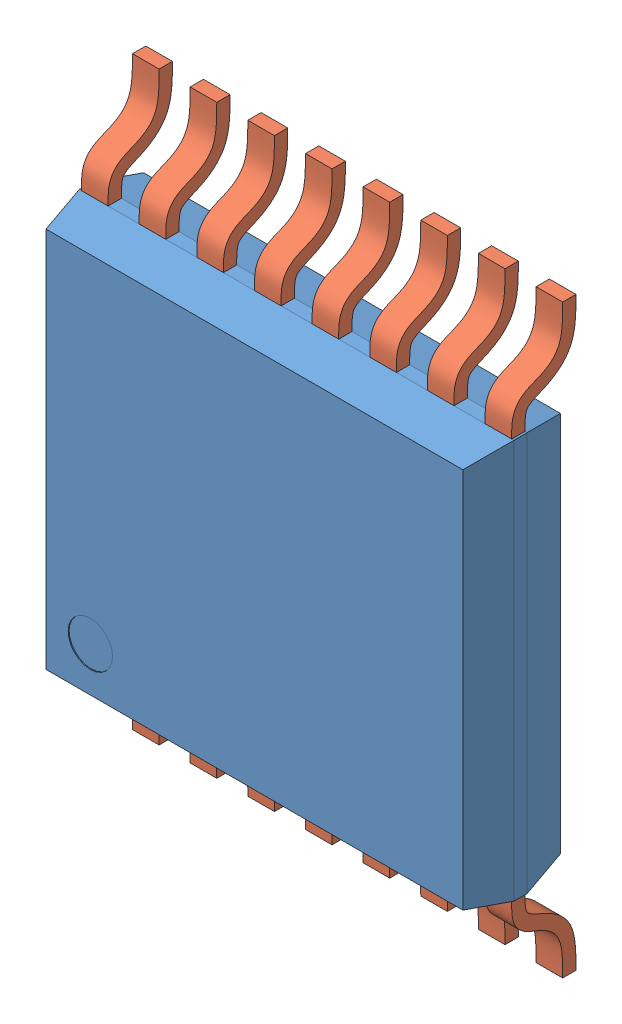
SolidWorks assembly Assem4, configuration Default. Lengths in mm.
Overall size (4.9 6.6 1.2).
17 component instances, 2 part files, 7 mates.
Components (placement in the parent):
- Body-1: Body [Default] at (0 0 0.65) size (4.9 4.5 1.1)
- Pin-1: Pin [Default] at (-2.275 -3.3 0.075) x (0 1 0) z (0 0 -1) size (1.05 0.3 0.73)
- Pin-2: Pin [Default] at (-1.625 -3.3 0.075) x (0 1 0) z (0 0 -1) size (1.05 0.3 0.73)
- Pin-3: Pin [Default] at (-0.975 -3.3 0.075) x (0 1 0) z (0 0 -1) size (1.05 0.3 0.73)
- Pin-4: Pin [Default] at (-0.325 -3.3 0.075) x (0 1 0) z (0 0 -1) size (1.05 0.3 0.73)
- Pin-5: Pin [Default] at (0.325 -3.3 0.075) x (0 1 0) z (0 0 -1) size (1.05 0.3 0.73)
- Pin-6: Pin [Default] at (0.975 -3.3 0.075) x (0 1 0) z (0 0 -1) size (1.05 0.3 0.73)
- Pin-7: Pin [Default] at (1.625 -3.3 0.075) x (0 1 0) z (0 0 -1) size (1.05 0.3 0.73)
- Pin-8: Pin [Default] at (2.275 -3.3 0.075) x (0 1 0) z (0 0 -1) size (1.05 0.3 0.73)
- Pin-9: Pin [Default] at (-2.275 3.3 0.075) x (0 -1 0) z (0 0 -1) size (1.05 0.3 0.73)
- Pin-10: Pin [Default] at (-1.625 3.3 0.075) x (0 -1 0) z (0 0 -1) size (1.05 0.3 0.73)
- Pin-11: Pin [Default] at (-0.975 3.3 0.075) x (0 -1 0) z (0 0 -1) size (1.05 0.3 0.73)
- Pin-12: Pin [Default] at (-0.325 3.3 0.075) x (0 -1 0) z (0 0 -1) size (1.05 0.3 0.73)
- Pin-13: Pin [Default] at (0.325 3.3 0.075) x (0 -1 0) z (0 0 -1) size (1.05 0.3 0.73)
- Pin-14: Pin [Default] at (0.975 3.3 0.075) x (0 -1 0) z (0 0 -1) size (1.05 0.3 0.73)
- Pin-15: Pin [Default] at (1.625 3.3 0.075) x (0 -1 0) z (0 0 -1) size (1.05 0.3 0.73)
- Pin-16: Pin [Default] at (2.275 3.3 0.075) x (0 -1 0) z (0 0 -1) size (1.05 0.3 0.73)
Mates (geometry in assembly coordinates):
- Distance3: distance = 0.65 mm: plane of assembly through (0 0 0) normal (0 0 1); plane of Body-1 through (0 0 0.65) normal (0 0 1)
- Coincident7: coincident: plane of Body-1 through (0 0 0.65) normal (0 1 0); plane of assembly through (0 0 0) normal (0 1 0)
- Coincident8: coincident: plane of Body-1 through (0 0 0.65) normal (1 0 0); plane of assembly through (0 0 0) normal (1 0 0)
- Coincident9: coincident: plane of Body-1 through (-2.45 -2.25 1.2) normal (0 -1 0); plane of Pin-1 through (-2.125 -2.25 0.575) normal (0 1 0)
- Parallel2: parallel: plane of Pin-1 through (-2.275 -3.3 0.075) normal (1 0 0); plane of assembly through (0 0 0) normal (1 0 0)
- Coincident11: coincident: line of Pin-1 through (0.3 -2.125 -3.3) axis (0 -1 0); plane of assembly
- Distance4: distance = 2.275 mm: plane of Pin-1 through (-2.275 -3.3 0.075) normal (1 0 0); plane of assembly through (0 0 0) normal (1 0 0)
